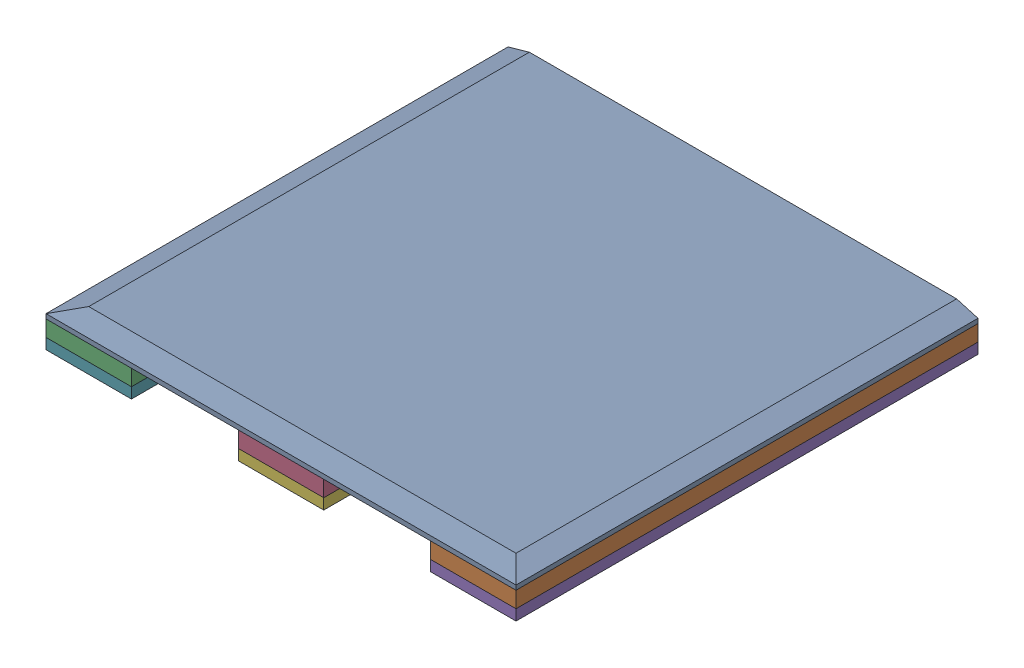
SolidWorks assembly GE-15020_ASM, configuration Default. Lengths in mm.
Overall size (558.8 44.45 549.27).
7 component instances, 3 part files, 0 mates.
Components (placement in the parent):
- GE-15020-01-1: GE-15020-01 [Default] at origin size (558.8 12.7 549.27)
- GE-15020-02-1: GE-15020-02 [Default] at (457.2 -19.05 0) size (101.6 19.05 549.27)
- GE-15020-02-2: GE-15020-02 [Default] at (0 -19.05 0) size (101.6 19.05 549.27)
- GE-15020-02-3: GE-15020-02 [Default] at (228.6 -19.05 0) size (101.6 19.05 549.27)
- GE-15020-03-1: GE-15020-03 [Default] at (457.2 -31.75 0) size (101.6 12.7 549.27)
- GE-15020-03-2: GE-15020-03 [Default] at (228.6 -31.75 0) size (101.6 12.7 549.27)
- GE-15020-03-3: GE-15020-03 [Default] at (0 -31.75 0) size (101.6 12.7 549.27)
